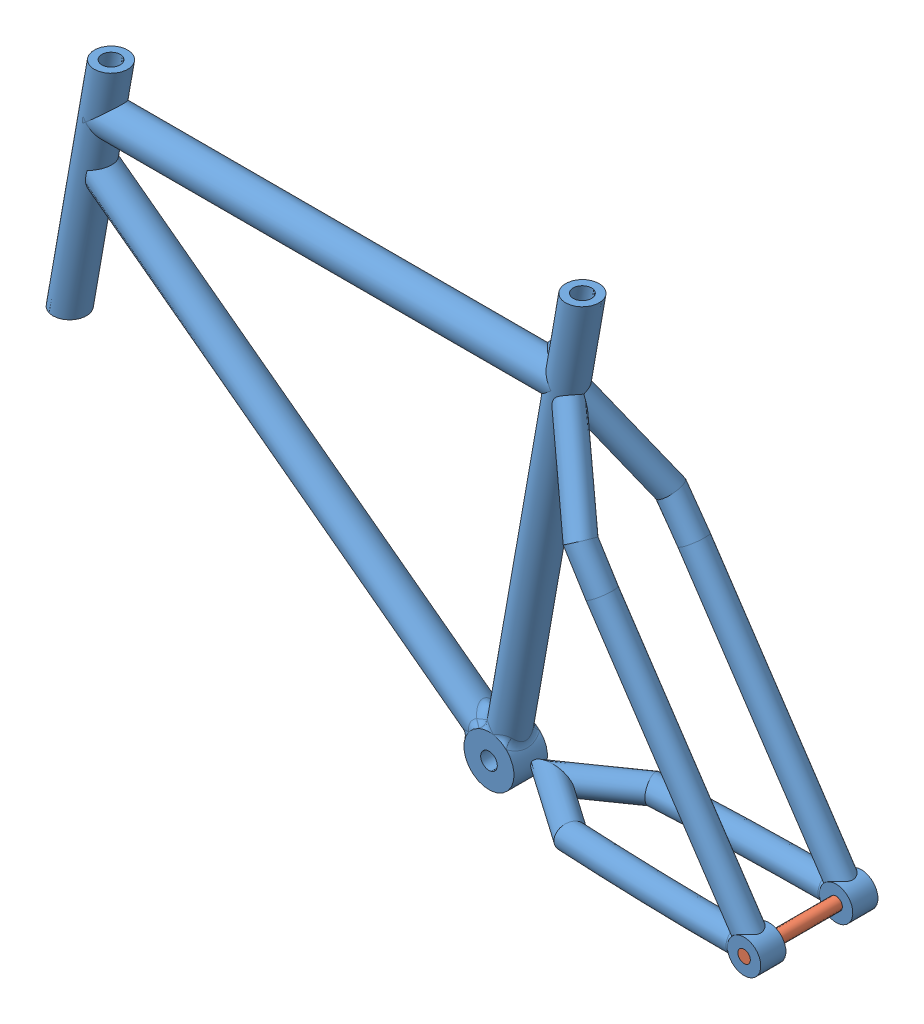
SolidWorks assembly EnsambleArmadura, configuration Predeterminado. Lengths in mm.
Overall size (1163.58 698.5 180.93).
2 component instances, 2 part files, 0 mates.
Components (placement in the parent):
- Armadura-1: Armadura [Predeterminado] at (202.0929 -203.5746 1452.7988) size (1163.58 698.5 180.93)
- UnionLlantaTrasera-1: UnionLlantaTrasera [Predeterminado] at (652.9429 -203.5746 1541.6988) x (0 0 -1) z (1 0 0) size (177.8 19.05 19.05)
